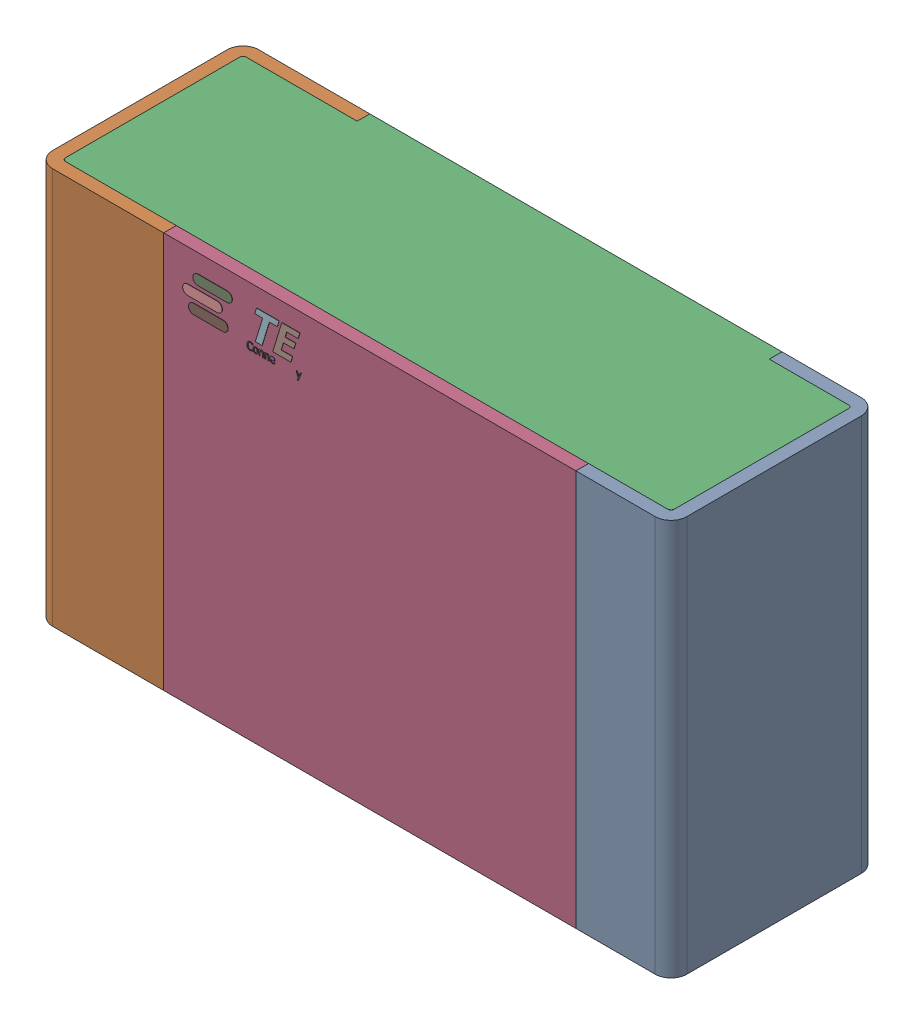
SolidWorks assembly R4.step, configuration Default. Lengths in mm.
Overall size (2 1.25 0.65).
5 component instances, 4 part files, 0 mates.
Components (placement in the parent):
- Res_TE_Connectivity_CPF0805B66R5E1_eec.step-1: Res_TE_Connectivity_CPF0805B66R5E1_eec.step [Default] at (51.169 22.987 0) size (2 1.25 0.65)
  - 1.step-1: 1.step [Default] at origin size (2 1.25 0.65)
  - 2.step-1: 2.step [Default] at origin size (1.92 1.25 0.61)
  - 3.step-1: 3.step [Default] at origin size (1.3 1.25 0.04)
  - TE connectivity Logo 1 (2).step-1: TE connectivity Logo 1 (2).step [Default] at (5.4285 0.313 0.551) x (-1 0 0) z (0 0 1) size (0.37 0.13 0.11)
